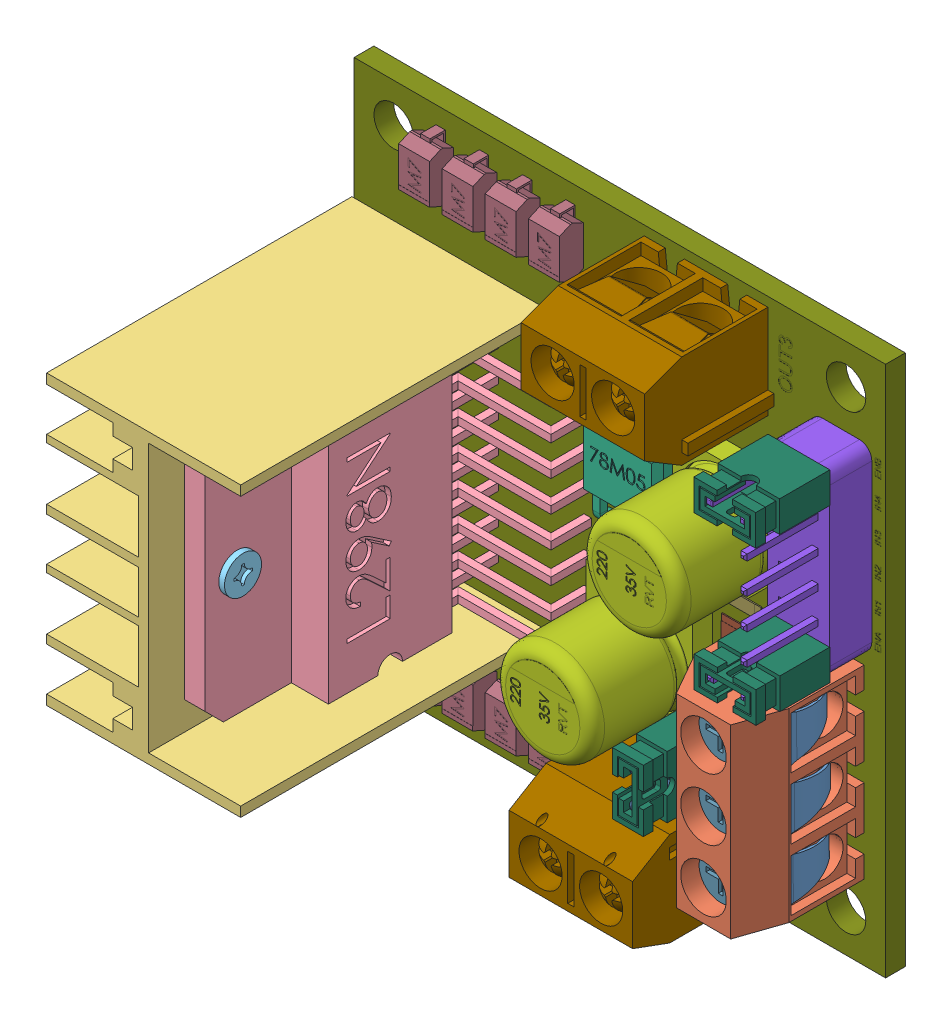
SolidWorks assembly placa_controlador_nueva v56, configuration Default. Lengths in mm.
Overall size (43.01 43 29.15).
33 component instances, 16 part files, 0 mates.
Components (placement in the parent):
- placa_controlador_nueva v56.step-1: placa_controlador_nueva v56.step [Default] at origin size (43.01 43 29.15)
  - Bornera_3h.step-1: Bornera_3h.step [Default] at (16 -0.4046 6.4336) x (1 0 0) z (0 -1 0) size (7.99 13.3 15.8)
    - parte de la bornera.step-1: parte de la bornera.step [Default] at (3.5365 -0.2135 12.4744) x (-0.001319 0.015134 -0.999885) z (-0.172987 0.984808 0.015134) size (3.8 1.71 4.12)
    - parte de la bornera.step-2: parte de la bornera.step [Default] at (3.6551 -0.2139 7.4069) x (0 0 -1) z (-0.173648 0.984808 0) size (3.8 1.71 4.12)
    - parte de la bornera.step-3: parte de la bornera.step [Default] at (3.6367 -0.3333 2.4659) x (0.000058 0.007266 -0.999974) z (-0.079257 0.996828 0.007238) size (3.8 1.71 4.12)
    - Bornera_3h-0.step-1: Bornera_3h-0.step [Default] at origin size (7.6 13.3 15.8)
  - disipador.step-1: disipador.step [Default] at (-5.8077 0.1751 14.1173) x (0 -1 0) z (-1 0 0) size (23.3 28.7 15.7)
  - Transistor L298N.step-1: Transistor L298N.step [Default] at (-13.3 0.1242 15.0782) x (1 0 0) z (0 -1 0) size (11 24 20.01)
  - Tornillo_disipador.step-1: Tornillo_disipador.step [Default] at (-11.6383 0.11 20.9475) x (0 0 -1) z (1 0 0) size (3 3 3.23)
  - INTEGRADO NUEVO 78M05.step-1: INTEGRADO NUEVO 78M05.step [Default] at (2 5 1.5) size (6.5 9.5 2.3)
  - capacitor nuevo.step-1: capacitor nuevo.step [Default] at (3.201 -6.9393 2.7384) x (0 1 0) z (1 0 0) size (8.6 9.81 8.6)
  - capacitor nuevo.step-2: capacitor nuevo.step [Default] at (10.201 5.4607 2.7384) x (0 1 0) z (1 0 0) size (8.6 9.81 8.6)
  - PINES.step-1: PINES.step [Default] at (20.3885 7.8202 3.2913) x (0 1 0) z (1 0 0) size (14.7 11.5 5)
  - bornera.step-1: bornera.step [Default] at (5.5 -17.5156 1.0655) x (1 0 0) z (0 -1 0) size (10.5 13.75 7.6)
  - bornera.step-2: bornera.step [Default] at (6.974 16.9345 1.5655) x (-1 0 0) z (0 1 0) size (10.5 13.75 7.6)
  - 2x1, Male, Header, 0.1in pitch.step-1: 2x1, Male, Header, 0.1in pitch.step [Default] at (9.27 -11.5524 2.8824) x (0 1 0) z (1 0 0) size (5.08 11.18 2.54)
  - resistencia 102.step-1: resistencia 102.step [Default] at (9.3004 -3.9988 1.6) x (0 -1 0) z (0 0 1) size (3 2 0.1)
  - led.step-1: led.step [Default] at (10 -1 1.6) size (3 1 0.1)
  - DIODO M7.step-1: DIODO M7.step [Default] at (-14.5017 -17.1506 1.8203) x (0 1 0) z (1 0 0) size (4.6 2.16 2.5)
  - DIODO M7.step-2: DIODO M7.step [Default] at (-11.0017 -17.1496 1.7903) x (0 1 0) z (1 0 0) size (4.6 2.16 2.5)
  - DIODO M7.step-3: DIODO M7.step [Default] at (-7.5017 -17.1496 1.7903) x (0 1 0) z (1 0 0) size (4.6 2.16 2.5)
  - DIODO M7.step-4: DIODO M7.step [Default] at (-4.0017 -17.1496 1.7903) x (0 1 0) z (1 0 0) size (4.6 2.16 2.5)
  - DIODO M7.step-5: DIODO M7.step [Default] at (-14.4997 17.8004 1.7903) x (0 1 0) z (1 0 0) size (4.6 2.16 2.5)
  - DIODO M7.step-6: DIODO M7.step [Default] at (-10.9917 17.8004 1.7903) x (0 1 0) z (1 0 0) size (4.6 2.16 2.5)
  - DIODO M7.step-7: DIODO M7.step [Default] at (-7.4916 17.8004 1.802) x (0 1 0) z (1 0 0) size (4.6 2.16 2.5)
  - DIODO M7.step-8: DIODO M7.step [Default] at (-3.9917 17.8004 1.8003) x (0 1 0) z (1 0 0) size (4.6 2.16 2.5)
  - pija_bornera de 3 pines.step-1: pija_bornera de 3 pines.step [Default] at (16.4 -12.9 9.8386) size (3.5 3.5 3.53)
  - pija_bornera de 3 pines.step-2: pija_bornera de 3 pines.step [Default] at (16.4 -7.91 9.839) size (3.5 3.5 3.53)
  - pija_bornera de 3 pines.step-3: pija_bornera de 3 pines.step [Default] at (16.4 -2.9 9.839) size (3.5 3.5 3.53)
  - Pin header jumper.step-1: Pin header jumper.step [Default] at (9.25 -11.55 4.2) x (0 1 0) z (0 0 1) size (5 2.5 6)
  - Pin header jumper.step-2: Pin header jumper.step [Default] at (19.16 1.6 5) x (-1 0 0) z (0 0 1) size (5 2.5 6)
  - Pin header jumper.step-3: Pin header jumper.step [Default] at (16.64 14 5) size (5 2.5 6)
  - placa_controlador_nueva.step-1: placa_controlador_nueva.step [Default] at origin size (43 43 1.6)
